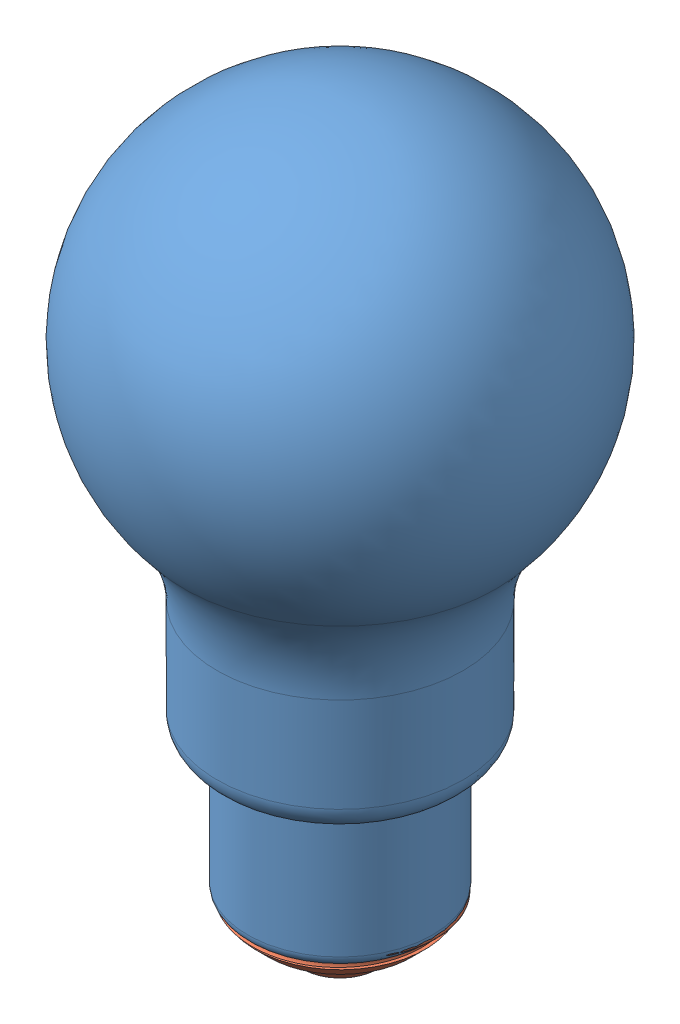
SolidWorks assembly Assem1, configuration Default. Lengths in mm.
Overall size (61.2 109.5 61.2).
2 component instances, 2 part files, 2 mates.
Components (placement in the parent):
- Bulb-1: Bulb [Default] at (43.0169 45.9017 79.6083) size (61.2 101.2 61.2)
- Part5-1: Part5 [Default] at (43.0169 34.5017 79.6083) x (0.088342 0 -0.99609) z (0.99609 0 0.088342) size (27.7 27.5 27.7)
Mates (geometry in assembly coordinates):
- Coincident1: coincident aligned: axis of Bulb-1 through (43.0169 44.6017 79.6083) axis (0 -1 0); axis of Part5-1 through (43.0169 54.5017 79.6083) axis (0 -1 0)
- Tangent1: tangent: torus of Bulb-1; plane of Part5-1 through (43.0169 54.5017 79.6083) normal (0 1 0)
